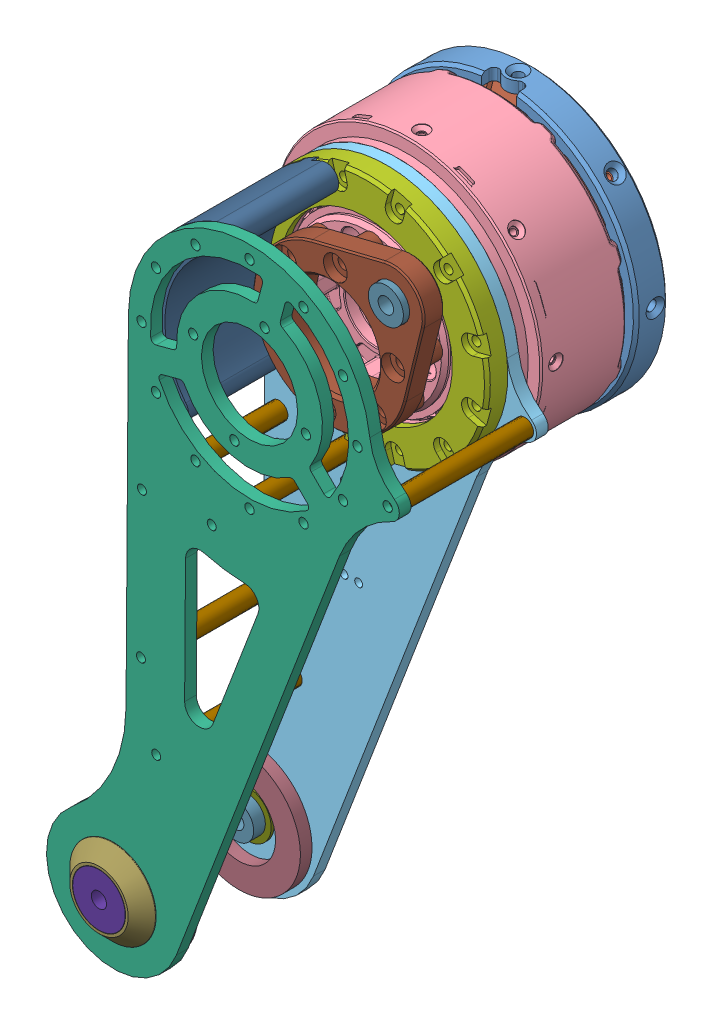
SolidWorks assembly HFE, configuration 默认. Lengths in mm.
Overall size (157.69 274.86 101.72).
34 component instances, 17 part files, 70 mates.
Components (placement in the parent):
- Elbow_motor_connector_1-1: Elbow_motor_connector_1 [默认] at (-10.2814 13.2836 99.5837) size (94 94 11.17)
- Elbow_motor_connector_2-1: Elbow_motor_connector_2 [默认] at (-10.2814 13.2836 94.5837) x (0 -1 0) z (0 0 1) size (86 86 9)
- gasket-1: gasket [默认] at (6.38 -0.697 94.5837) x (-0.383049 0.923728 0) z (0 0 -1) size (6 6 1)
- gasket-2: gasket [默认] at (6.38 27.2642 94.5837) x (-0.383049 0.923728 0) z (0 0 -1) size (6 6 1)
- gasket-3: gasket [默认] at (-10.2814 -8.4664 94.5837) x (-0.383049 0.923728 0) z (0 0 -1) size (6 6 1)
- gasket-4: gasket [默认] at (-26.9429 -0.697 94.5837) x (-0.383049 0.923728 0) z (0 0 -1) size (6 6 1)
- gasket-5: gasket [默认] at (-26.9429 27.2642 94.5837) x (-0.383049 0.923728 0) z (0 0 -1) size (6 6 1)
- Power_unit-1: Power_unit [默认] at (-10.2814 13.2836 134.6337) x (0.707107 -0.707107 0) z (0 0 1) size (92.01 92.01 49.55)
- 大腿侧板-2: 大腿侧板 [默认] at (-10.2814 13.2836 138.1337) x (0 0 -1) z (0.965926 -0.258819 0) size (4 244.5 94.5)
- 大腿侧板wai-2: 大腿侧板wai [默认] at (-10.2814 13.2836 185.1337) x (0 0 -1) z (0.965926 -0.258819 0) size (4 244.5 94.5)
- 轴承压紧件-1: 轴承压紧件 [默认] at (-10.2814 13.2836 138.1337) x (0 0 1) z (0.965926 0.258819 0) size (7 83 83)
- M3-40铝柱-1: M3-40铝柱 [默认] at (-42.3244 -5.2164 143.1337) x (-0.026985 0.999636 0) z (0 0 1) size (6 6 40)
- M3-40铝柱-4: M3-40铝柱 [默认] at (-28.7814 45.3266 143.1337) x (0.882691 -0.469953 0) z (0 0 1) size (6 6 40)
- M3-40铝柱-5: M3-40铝柱 [默认] at (-42.3244 31.7836 143.1337) x (0.91639 -0.400286 0) z (0 0 1) size (6 6 40)
- M3-40铝柱-6: M3-40铝柱 [默认] at (-47.2814 13.2836 143.1337) x (0.91639 -0.400286 0) z (0 0 1) size (6 6 40)
- 45mm铝柱-1: 45mm铝柱 [默认] at (37.0489 0.6015 183.1337) x (0.98066 0.195717 0) z (-0.195717 0.98066 0) size (6 45 6)
- 大腿填充-1: 大腿填充 [默认] at (-10.2814 13.2836 143.1337) x (0 0 1) z (-0.5 0.866025 0) size (38.05 51.45 53.6)
- 四连杆电机垫环-1: 四连杆电机垫环 [默认] at (-10.2814 13.2836 144.6337) x (0 0 1) z (-0.707107 -0.707107 0) size (13 53 67.5)
- 45mm铝柱-2: 45mm铝柱 [默认] at (-23.2224 -35.0127 183.1337) x (0.98066 0.195717 0) z (-0.195717 0.98066 0) size (6 45 6)
- 45mm铝柱-3: 45mm铝柱 [默认] at (-47.1289 -36.4609 183.1337) x (0.98066 0.195717 0) z (-0.195717 0.98066 0) size (6 45 6)
- 45mm铝柱-4: 45mm铝柱 [默认] at (-47.4772 -86.4597 183.1337) x (0.98066 0.195717 0) z (-0.195717 0.98066 0) size (6 45 6)
- 45mm铝柱-5: 45mm铝柱 [默认] at (-42.2414 -112.7386 183.1337) x (0.98066 0.195717 0) z (-0.195717 0.98066 0) size (6 45 6)
- 关节挡边件-1: 关节挡边件 [默认] at (-56.8689 -160.583 185.1337) x (1 0 0) z (0 -1 0) size (29.43 5 29.43)
- 关节挡边件-2: 关节挡边件 [默认] at (-56.8689 -160.583 134.1337) x (1 0 0) z (0 1 0) size (29.43 5 29.43)
- 25-42-6推力轴承-1: 25-42-6推力轴承 [默认] at (-56.8689 -160.583 181.1337) x (0 0 -1) z (0.99864 -0.052132 0) size (4 42 42)
- 5-12-4推力轴承-1: 5-12-4推力轴承 [默认] at (-56.8689 -160.583 180.1337) x (1 0 0) z (0 1 0) size (12 4 12)
- 5-13-4挡边轴承-1: 5-13-4挡边轴承 [默认] at (10.9318 34.4968 154.6337) x (-0.998447 -0.055713 0) z (0.055713 -0.998447 0) size (15 4 15)
- 5-14-5挡边轴承-1: 5-14-5挡边轴承 [默认] at (-56.8689 -160.583 134.1337) x (-0.843229 0.537555 0) z (0.537555 0.843229 0) size (16 5 16)
- 5-16-5挡边轴承-1: 5-16-5挡边轴承 [默认] at (-56.8689 -160.583 134.1337) x (0.848633 0.528982 0) z (-0.528982 0.848633 0) size (18 5 18)
- 5-16-5挡边轴承-2: 5-16-5挡边轴承 [默认] at (-56.8689 -160.583 185.1337) x (-0.986532 0.163568 0) z (0.163568 0.986532 0) size (18 5 18)
- 5-12-4推力轴承-2: 5-12-4推力轴承 [默认] at (-56.8689 -160.583 143.1337) x (0.80849 0.588511 0) z (-0.588511 0.80849 0) size (12 4 12)
- 25-42-6推力轴承-2: 25-42-6推力轴承 [默认] at (-56.8689 -160.583 142.1337) x (0 0 -1) z (0.99864 -0.052132 0) size (4 42 42)
- 5-14-5挡边轴承-2: 5-14-5挡边轴承 [默认] at (-56.8689 -160.583 185.1337) x (0.416809 0.908994 0) z (-0.908994 0.416809 0) size (16 5 16)
- 5-12-4推力轴承-3: 5-12-4推力轴承 [默认] at (10.9318 34.4968 159.6337) x (0.815764 0.578385 0) z (-0.578385 0.815764 0) size (12 4 12)
Mates (geometry in assembly coordinates):
- 同心1: concentric aligned: cylinder of gasket-1 through (6.38 -0.697 93.5837) axis (0 0 1) radius 2.25; cylinder of Elbow_motor_connector_2-1 through (6.38 -0.697 97.5837) axis (0 0 1) radius 2.25
- 重合1: coincident anti-aligned: plane of Elbow_motor_connector_2-1 through (-10.2814 13.2836 94.5837) normal (0 0 -1); plane of gasket-1 through (6.38 -0.697 94.5837) normal (0 0 1)
- 同心2: concentric aligned: cylinder of Elbow_motor_connector_2-1 through (-26.9429 27.2642 97.5837) axis (0 0 1) radius 2.25; cylinder of gasket-5 through (-26.9429 27.2642 93.5837) axis (0 0 1) radius 2.25
- 重合2: coincident anti-aligned: plane of Elbow_motor_connector_2-1 through (-10.2814 13.2836 94.5837) normal (0 0 -1); plane of gasket-5 through (-26.9429 27.2642 94.5837) normal (0 0 1)
- 同心3: concentric aligned: cylinder of Elbow_motor_connector_2-1 through (-26.9429 -0.697 97.5837) axis (0 0 1) radius 2.25; cylinder of gasket-4 through (-26.9429 -0.697 93.5837) axis (0 0 1) radius 2.25
- 重合3: coincident anti-aligned: plane of Elbow_motor_connector_2-1 through (-10.2814 13.2836 94.5837) normal (0 0 -1); plane of gasket-4 through (-26.9429 -0.697 94.5837) normal (0 0 1)
- 重合4: coincident anti-aligned: plane of Elbow_motor_connector_2-1 through (-10.2814 13.2836 94.5837) normal (0 0 -1); plane of gasket-3 through (-10.2814 -8.4664 94.5837) normal (0 0 1)
- 同心4: concentric aligned: cylinder of Elbow_motor_connector_2-1 through (-10.2814 -8.4664 97.5837) axis (0 0 1) radius 2.25; cylinder of gasket-3 through (-10.2814 -8.4664 93.5837) axis (0 0 1) radius 2.25
- 同心5: concentric aligned: cylinder of Elbow_motor_connector_2-1 through (6.38 27.2642 97.5837) axis (0 0 1) radius 2.25; cylinder of gasket-2 through (6.38 27.2642 93.5837) axis (0 0 1) radius 2.25
- 重合5: coincident anti-aligned: plane of Elbow_motor_connector_2-1 through (-10.2814 13.2836 94.5837) normal (0 0 -1); plane of gasket-2 through (6.38 27.2642 94.5837) normal (0 0 1)
- 同心6: concentric aligned: cylinder of Elbow_motor_connector_1-1 through (-10.2814 60.2836 93.0837) axis (0 1 0) radius 1.7; cylinder of Elbow_motor_connector_2-1 through (-10.2814 56.2836 93.0837) axis (0 1 0) radius 1.25
- 同心7: concentric aligned: cylinder of Elbow_motor_connector_1-1 through (-10.2814 13.2836 88.5837) axis (0 0 1) radius 47; cylinder of Elbow_motor_connector_2-1 through (-10.2814 13.2836 88.5837) axis (0 0 1) radius 43
- 同心8: concentric anti-aligned: cylinder of Elbow_motor_connector_1-1 through (5.9826 52.5485 88.5837) axis (0 0 -1) radius 1.95; cylinder of Power_unit-1 through (5.9826 52.5485 104.0837) axis (0 0 1) radius 1.45
- 同心9: concentric anti-aligned: cylinder of Elbow_motor_connector_1-1 through (-26.5455 52.5485 88.5837) axis (0 0 -1) radius 1.95; cylinder of Power_unit-1 through (-26.5455 52.5485 104.0837) axis (0 0 1) radius 1.45
- 重合6: coincident anti-aligned: plane of Elbow_motor_connector_1-1 through (-10.2814 13.2836 99.5837) normal (0 0 1); plane of Power_unit-1 through (-10.2814 13.2836 99.5837) normal (0 0 -1)
- 同心10: concentric aligned: cylinder of Power_unit-1 through (-19.8577 -22.4556 134.1337) axis (0 0 1) radius 1.25; cylinder of 大腿侧板-2 through (-19.8577 -22.4556 133.1337) axis (0 0 1) radius 1.6
- 重合7: coincident anti-aligned: plane of Power_unit-1 through (-10.2814 13.2836 134.1337) normal (0 0 1); plane of 大腿侧板-2 through (-10.2814 13.2836 134.1337) normal (0 0 -1)
- 同心11: concentric aligned: cylinder of Power_unit-1 through (-0.7051 49.0229 134.1337) axis (0 0 1) radius 1.25; cylinder of 大腿侧板-2 through (-0.7051 49.0229 133.1337) axis (0 0 1) radius 1.6
- 同心12: concentric anti-aligned: cylinder of 大腿侧板-2 through (-19.8577 49.0229 133.1337) axis (0 0 1) radius 1.6; cylinder of 轴承压紧件-1 through (-19.8577 49.0229 146.1337) axis (0 0 -1) radius 1.55
- 同心13: concentric anti-aligned: cylinder of 大腿侧板-2 through (-0.7051 49.0229 133.1337) axis (0 0 1) radius 1.6; cylinder of 轴承压紧件-1 through (-0.7051 49.0229 146.1337) axis (0 0 -1) radius 1.55
- 重合8: coincident anti-aligned: plane of 大腿侧板-2 through (-10.2814 13.2836 138.1337) normal (0 0 1); plane of 轴承压紧件-1 through (-10.2814 13.2836 138.1337) normal (0 0 -1)
- 重合9: coincident anti-aligned: plane of 轴承压紧件-1 through (-10.2814 13.2836 143.1337) normal (0 0 1); plane of M3-40铝柱-1 through (-42.3244 -5.2164 143.1337) normal (0 0 -1)
- 重合10: coincident anti-aligned: plane of 轴承压紧件-1 through (-10.2814 13.2836 143.1337) normal (0 0 1); plane of M3-40铝柱-6 through (-47.2814 13.2836 143.1337) normal (0 0 -1)
- 同心16: concentric anti-aligned: cylinder of 大腿侧板-2 through (37.0489 0.6015 138.1337) axis (0 0 -1) radius 1.6; cylinder of 45mm铝柱-1 through (37.0489 0.6015 138.1337) axis (0 0 1) radius 1.6
- 重合11: coincident anti-aligned: plane of 大腿侧板-2 through (-10.2814 13.2836 138.1337) normal (0 0 1); plane of 45mm铝柱-1 through (37.0489 0.6015 138.1337) normal (0 0 -1)
- 同心17: concentric aligned: cylinder of 轴承压紧件-1 through (-42.3244 -5.2164 148.1337) axis (0 0 -1) radius 1.6; cylinder of M3-40铝柱-1 through (-42.3244 -5.2164 183.1337) axis (0 0 -1) radius 1.65
- 同心18: concentric aligned: cylinder of 轴承压紧件-1 through (-47.2814 13.2836 148.1337) axis (0 0 -1) radius 1.6; cylinder of M3-40铝柱-6 through (-47.2814 13.2836 183.1337) axis (0 0 -1) radius 1.65
- 重合12: coincident anti-aligned: plane of 轴承压紧件-1 through (-10.2814 13.2836 143.1337) normal (0 0 1); plane of M3-40铝柱-5 through (-42.3244 31.7836 143.1337) normal (0 0 -1)
- 同心19: concentric aligned: cylinder of 轴承压紧件-1 through (-42.3244 31.7836 148.1337) axis (0 0 -1) radius 1.6; cylinder of M3-40铝柱-5 through (-42.3244 31.7836 183.1337) axis (0 0 -1) radius 1.65
- 同心20: concentric aligned: cylinder of 轴承压紧件-1 through (-28.7814 45.3266 148.1337) axis (0 0 -1) radius 1.6; cylinder of M3-40铝柱-4 through (-28.7814 45.3266 183.1337) axis (0 0 -1) radius 1.65
- 重合13: coincident anti-aligned: plane of 轴承压紧件-1 through (-10.2814 13.2836 143.1337) normal (0 0 1); plane of M3-40铝柱-4 through (-28.7814 45.3266 143.1337) normal (0 0 -1)
- 同心21: concentric aligned: cylinder of M3-40铝柱-5 through (-42.3244 31.7836 183.1337) axis (0 0 -1) radius 3; cylinder of 大腿填充-1 through (-42.3244 31.7836 181.1337) axis (0 0 -1) radius 3.15
- 同心22: concentric aligned: cylinder of M3-40铝柱-4 through (-28.7814 45.3266 183.1337) axis (0 0 -1) radius 3; cylinder of 大腿填充-1 through (-28.7814 45.3266 181.1337) axis (0 0 -1) radius 3.15
- 重合14: coincident anti-aligned: plane of 轴承压紧件-1 through (-10.2814 13.2836 145.1337) normal (0 0 1); plane of 大腿填充-1 through (-31.704 18.1775 145.1337) normal (0 0 -1)
- 同心23: concentric anti-aligned: cylinder of Power_unit-1 through (5.0981 -2.096 144.6337) axis (0 0 1) radius 1.65; cylinder of 四连杆电机垫环-1 through (5.0981 -2.096 154.6337) axis (0 0 -1) radius 2.05
- 同心24: concentric anti-aligned: cylinder of Power_unit-1 through (-25.661 28.6632 144.6337) axis (0 0 1) radius 1.65; cylinder of 四连杆电机垫环-1 through (-25.661 28.6632 154.6337) axis (0 0 -1) radius 2.05
- 重合15: coincident anti-aligned: plane of Power_unit-1 through (-10.2814 13.2836 144.6337) normal (0 0 1); plane of 四连杆电机垫环-1 through (-10.2814 13.2836 144.6337) normal (0 0 -1)
- 同心25: concentric anti-aligned: cylinder of 大腿侧板-2 through (-23.2224 -35.0127 144.1337) axis (0 0 -1) radius 1.55; cylinder of 45mm铝柱-2 through (-23.2224 -35.0127 138.1337) axis (0 0 1) radius 1.6
- 同心26: concentric anti-aligned: cylinder of 大腿侧板-2 through (-47.1289 -36.4609 144.1337) axis (0 0 -1) radius 1.55; cylinder of 45mm铝柱-3 through (-47.1289 -36.4609 138.1337) axis (0 0 1) radius 1.6
- 重合16: coincident anti-aligned: plane of 大腿侧板-2 through (-10.2814 13.2836 138.1337) normal (0 0 1); plane of 45mm铝柱-3 through (-47.1289 -36.4609 138.1337) normal (0 0 -1)
- 重合17: coincident anti-aligned: plane of 大腿侧板-2 through (-10.2814 13.2836 138.1337) normal (0 0 1); plane of 45mm铝柱-2 through (-23.2224 -35.0127 138.1337) normal (0 0 -1)
- 重合18: coincident anti-aligned: plane of 大腿侧板-2 through (-10.2814 13.2836 138.1337) normal (0 0 1); plane of 45mm铝柱-4 through (-47.4772 -86.4597 138.1337) normal (0 0 -1)
- 同心27: concentric anti-aligned: cylinder of 大腿侧板-2 through (-47.4772 -86.4597 144.1337) axis (0 0 -1) radius 1.55; cylinder of 45mm铝柱-4 through (-47.4772 -86.4597 138.1337) axis (0 0 1) radius 1.6
- 同心28: concentric anti-aligned: cylinder of 大腿侧板-2 through (-42.2414 -112.7386 144.1337) axis (0 0 -1) radius 1.55; cylinder of 45mm铝柱-5 through (-42.2414 -112.7386 138.1337) axis (0 0 1) radius 1.6
- 重合19: coincident anti-aligned: plane of 大腿侧板-2 through (-10.2814 13.2836 138.1337) normal (0 0 1); plane of 45mm铝柱-5 through (-42.2414 -112.7386 138.1337) normal (0 0 -1)
- 同心29: concentric anti-aligned: cylinder of 大腿侧板wai-2 through (37.0489 0.6015 199.3016) axis (0 0 -1) radius 1.6; cylinder of 45mm铝柱-1 through (37.0489 0.6015 138.1337) axis (0 0 1) radius 1.6
- 同心30: concentric anti-aligned: cylinder of 大腿侧板wai-2 through (-42.2414 -112.7386 191.1337) axis (0 0 -1) radius 1.55; cylinder of 45mm铝柱-5 through (-42.2414 -112.7386 138.1337) axis (0 0 1) radius 1.6
- 重合20: coincident anti-aligned: plane of 大腿侧板wai-2 through (-10.2814 13.2836 181.1337) normal (0 0 -1); plane of 大腿填充-1 through (-10.2814 13.2836 181.1337) normal (0 0 1)
- 重合21: coincident anti-aligned: plane of 大腿侧板wai-2 through (-10.2814 13.2836 185.1337) normal (0 0 1); plane of 关节挡边件-1 through (-56.8689 -160.583 185.1337) normal (0 0 -1)
- 同心31: concentric anti-aligned: cylinder of 大腿侧板wai-2 through (-56.8689 -160.583 181.1337) axis (0 0 1) radius 7.1; cylinder of 关节挡边件-1 through (-56.8689 -160.583 190.1337) axis (0 0 -1) radius 8.1
- 重合22: coincident anti-aligned: plane of 大腿侧板-2 through (-10.2814 13.2836 134.1337) normal (0 0 -1); plane of 关节挡边件-2 through (-56.8689 -160.583 134.1337) normal (0 0 1)
- 同心32: concentric aligned: cylinder of 大腿侧板-2 through (-56.8689 -160.583 133.1337) axis (0 0 1) radius 7.075; cylinder of 关节挡边件-2 through (-56.8689 -160.583 129.1337) axis (0 0 1) radius 8.1
- 同心33: concentric aligned: cylinder of 关节挡边件-2 through (-56.8689 -160.583 129.1337) axis (0 0 1) radius 8.1; cylinder of 5-16-5挡边轴承-1 through (-56.8689 -160.583 129.1337) axis (0 0 1) radius 8
- 重合23: coincident anti-aligned: plane of 关节挡边件-2 through (-56.8689 -160.583 130.1337) normal (0 0 -1); plane of 5-16-5挡边轴承-1 through (-56.8689 -160.583 130.1337) normal (0 0 1)
- 重合24: coincident anti-aligned: plane of 关节挡边件-1 through (-56.8689 -160.583 189.1337) normal (0 0 1); plane of 5-16-5挡边轴承-2 through (-56.8689 -160.583 189.1337) normal (0 0 -1)
- 同心34: concentric aligned: cylinder of 关节挡边件-1 through (-56.8689 -160.583 190.1337) axis (0 0 -1) radius 8.1; cylinder of 5-16-5挡边轴承-2 through (-56.8689 -160.583 190.1337) axis (0 0 -1) radius 8
- 重合27: coincident anti-aligned: plane of 大腿侧板wai-2 through (-10.2814 13.2836 181.1337) normal (0 0 -1); plane of 25-42-6推力轴承-1 through (-56.8689 -160.583 181.1337) normal (0 0 1)
- 重合29: coincident anti-aligned: plane of 大腿侧板-2 through (-10.2814 13.2836 138.1337) normal (0 0 1); plane of 25-42-6推力轴承-2 through (-56.8689 -160.583 138.1337) normal (0 0 -1)
- 重合31: coincident anti-aligned: plane of 大腿侧板-2 through (-10.2814 13.2836 138.1337) normal (0 0 1); plane of 5-14-5挡边轴承-1 through (-56.8689 -160.583 138.1337) normal (0 0 -1)
- 同心42: concentric anti-aligned: cylinder of 大腿侧板-2 through (-56.8689 -160.583 133.1337) axis (0 0 1) radius 7.075; cylinder of 5-14-5挡边轴承-1 through (-56.8689 -160.583 139.1337) axis (0 0 -1) radius 7
- 同心43: concentric anti-aligned: cylinder of 5-14-5挡边轴承-1 through (-56.8689 -160.583 139.1337) axis (0 0 -1) radius 2.6; cylinder of 5-12-4推力轴承-2 through (-56.8689 -160.583 139.1337) axis (0 0 1) radius 6
- 重合32: coincident anti-aligned: plane of 5-14-5挡边轴承-1 through (-56.8689 -160.583 139.1337) normal (0 0 1); plane of 5-12-4推力轴承-2 through (-56.8689 -160.583 139.1337) normal (0 0 -1)
- 同心44: concentric aligned: cylinder of 大腿侧板wai-2 through (-56.8689 -160.583 181.1337) axis (0 0 1) radius 7.1; cylinder of 5-14-5挡边轴承-2 through (-56.8689 -160.583 180.1337) axis (0 0 1) radius 7
- 重合33: coincident anti-aligned: plane of 大腿侧板wai-2 through (-10.2814 13.2836 181.1337) normal (0 0 -1); plane of 5-14-5挡边轴承-2 through (-56.8689 -160.583 181.1337) normal (0 0 1)
- 重合34: coincident anti-aligned: plane of 5-12-4推力轴承-1 through (-56.8689 -160.583 180.1337) normal (0 0 1); plane of 5-14-5挡边轴承-2 through (-56.8689 -160.583 180.1337) normal (0 0 -1)
- 同心45: concentric aligned: cylinder of 5-12-4推力轴承-1 through (-56.8689 -160.583 176.1337) axis (0 0 1) radius 6; cylinder of 5-14-5挡边轴承-2 through (-56.8689 -160.583 180.1337) axis (0 0 1) radius 2.6
- 同心46: concentric anti-aligned: cylinder of 四连杆电机垫环-1 through (10.9318 34.4968 154.6337) axis (0 0 -1) radius 6.6; cylinder of 5-13-4挡边轴承-1 through (10.9318 34.4968 150.6337) axis (0 0 1) radius 6.5
- 重合35: coincident anti-aligned: plane of 四连杆电机垫环-1 through (10.9318 34.4968 154.6337) normal (0 0 -1); plane of 5-13-4挡边轴承-1 through (10.9318 34.4968 154.6337) normal (0 0 1)
- 同心47: concentric aligned: cylinder of 四连杆电机垫环-1 through (10.9318 34.4968 155.6337) axis (0 0 1) radius 6.15; cylinder of 5-12-4推力轴承-3 through (10.9318 34.4968 155.6337) axis (0 0 1) radius 6
- 重合36: coincident anti-aligned: plane of 四连杆电机垫环-1 through (10.9318 34.4968 155.6337) normal (0 0 1); plane of 5-12-4推力轴承-3 through (10.9318 34.4968 155.6337) normal (0 0 -1)
